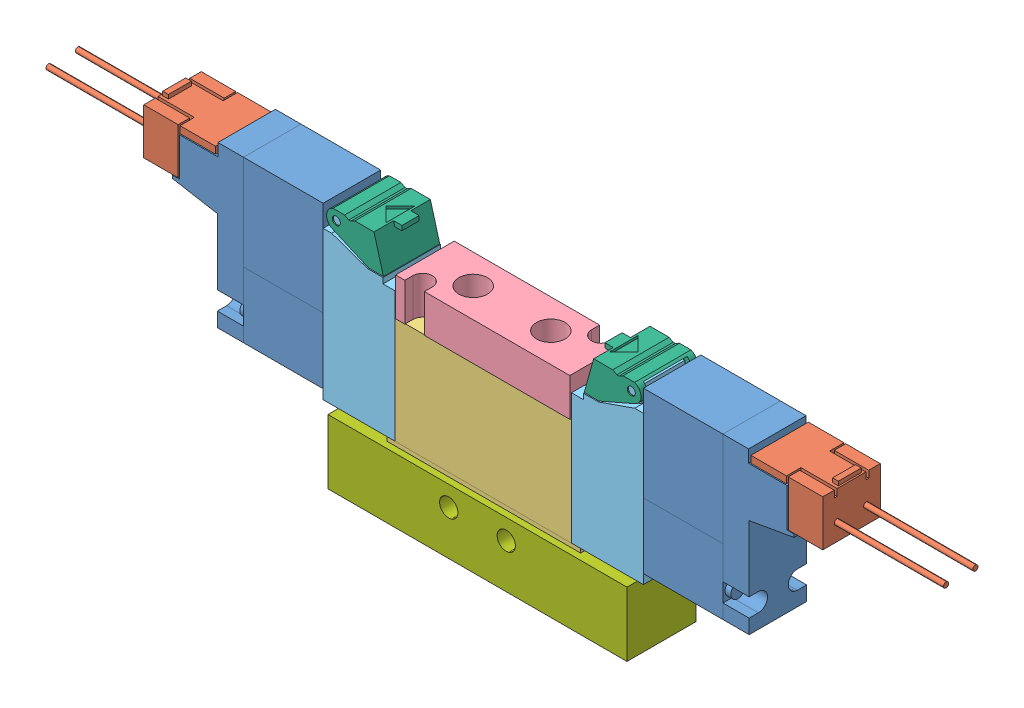
SolidWorks assembly 4GA120-M5-E01-4, configuration Default. Lengths in mm.
Overall size (156.1 41.8 12).
14 component instances, 7 part files, 0 mates.
Components (placement in the parent):
- 4GA120-M5-E01-4_4GA129-M5-E-3-1: 4GA120-M5-E01-4_4GA129-M5-E-3 [Default] x (0 0 -1) z (1 0 0) size (10.2 30.4 156.1)
  - 4GA120-M5-E01-4_D_100000_4G-Coil-SubASSY_01(EDC-E-H)-1: 4GA120-M5-E01-4_D_100000_4G-Coil-SubASSY_01(EDC-E-H) [Default] at (0 2.46 -27.85) size (10 27.94 50.2)
    - 4GA120-M5-E01-4_D_000102_4GcoilEDC_00(Default)-1: 4GA120-M5-E01-4_D_000102_4GcoilEDC_00(Default) [Default] at origin size (10 27.94 26.2)
    - 4GA120-M5-E01-4_D_000123_4GSocketAssyE_00(Default)-1: 4GA120-M5-E01-4_D_000123_4GSocketAssyE_00(Default) [Default] at (0 22.17 -25.2) size (10 8.7 31.5)
  - 4GA120-M5-E01-4_D_100000_4G-Coil-SubASSY_01(EDC-E-H)-1-1: 4GA120-M5-E01-4_D_100000_4G-Coil-SubASSY_01(EDC-E-H)-1 [Default] at (0 2.46 27.85) x (-1 0 0) z (0 0 -1) size (10 27.94 50.2)
    - 4GA120-M5-E01-4_D_000102_4GcoilEDC_00(Default)-1: 4GA120-M5-E01-4_D_000102_4GcoilEDC_00(Default) [Default] at origin size (10 27.94 26.2)
    - 4GA120-M5-E01-4_D_000123_4GSocketAssyE_00(Default)-1: 4GA120-M5-E01-4_D_000123_4GSocketAssyE_00(Default) [Default] at (0 22.17 -25.2) size (10 8.7 31.5)
  - 4GA120-M5-E01-4_D_000091_4G1Body_00(Default)-1: 4GA120-M5-E01-4_D_000091_4G1Body_00(Default) [Default] at origin size (10 19.4 33.7)
  - 4GA120-M5-E01-4_D_000100_4G1PlateM5_00(Default)-1: 4GA120-M5-E01-4_D_000100_4G1PlateM5_00(Default) [Default] at (0 19.4 0) size (10.2 6.6 30.3)
  - 4GA120-M5-E01-4_D_000097_4G1PistonAssy_00(Default)-1: 4GA120-M5-E01-4_D_000097_4G1PistonAssy_00(Default) [Default] at (0 0.8 15.35) x (-1 0 0) z (0 0 -1) size (10 28.72 12.5)
  - 4GA120-M5-E01-4_D_000097_4G1PistonAssy_00(Default)-2: 4GA120-M5-E01-4_D_000097_4G1PistonAssy_00(Default) [Default] at (0 0.8 -15.35) size (10 28.72 12.5)
  - 4GA120-M5-E01-4_D_000094_4G1ManualCover_00(Default)-1: 4GA120-M5-E01-4_D_000094_4G1ManualCover_00(Default) [Default] at (0 28.8 25.65) x (-1 0 0) z (0 0 -1) size (9.8 5.9 9.89)
  - 4GA120-M5-E01-4_D_000094_4G1ManualCover_00(Default)-2: 4GA120-M5-E01-4_D_000094_4G1ManualCover_00(Default) [Default] at (0 28.8 -25.65) size (9.8 5.9 9.89)
- 4GA120-M5-E01-4_4GA1JOINTADAPTOR-1: 4GA120-M5-E01-4_4GA1JOINTADAPTOR [Default] at origin size (52 11.4 12)
